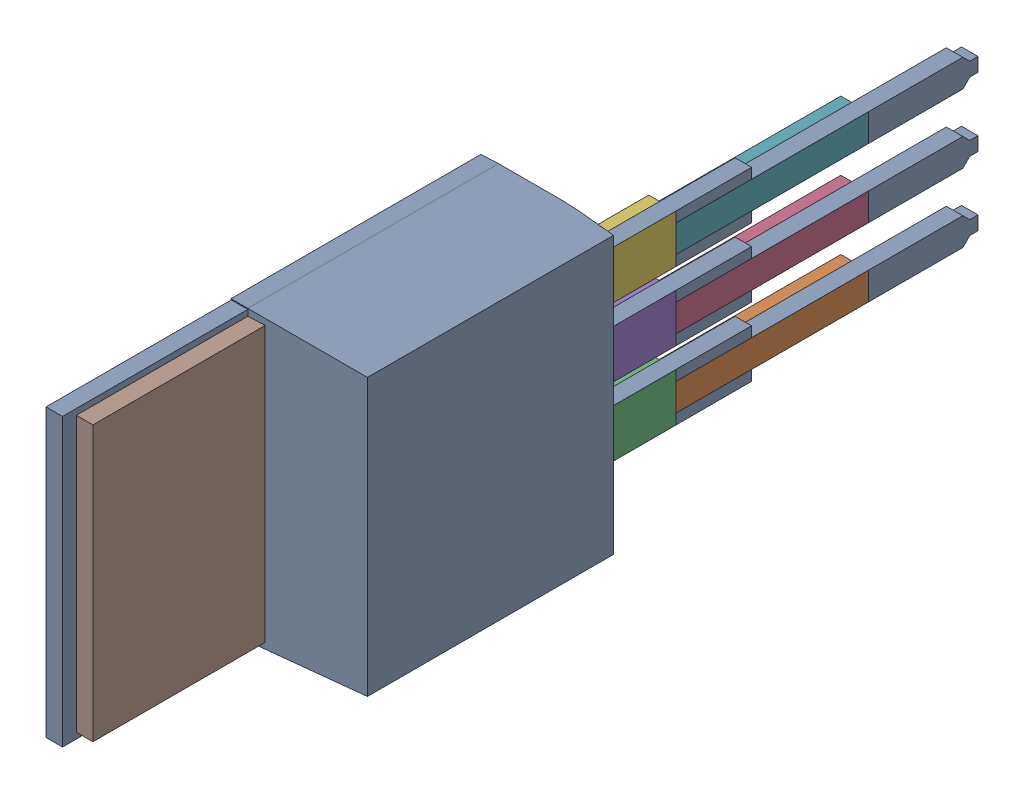
SolidWorks assembly Q2, configuration Default. Lengths in mm.
Overall size (4.86 10.67 30.99).
15 component instances, 4 part files, 0 mates.
Components (placement in the parent):
- 42ctq030-1: 42ctq030 [Default] at (98.0452 35.6871 7.62) x (0 1 0) z (1 0 0) size (10.67 30.99 4.83)
- 809727544-1: 809727544 [Default] at (97.5373 33.147 -3.048) size (1.02 1.02 7.11)
  - Extruded-1: Extruded [Default] at origin size (1.02 1.02 7.11)
- 809727680-1: 809727680 [Default] at (97.5373 33.147 4.064) size (1.02 1.78 4.06)
  - Extruded_2-1: Extruded_2 [Default] at origin size (1.02 1.78 4.06)
- 809727544-2: 809727544 [Default] at (97.5373 35.687 -3.048) size (1.02 1.02 7.11)
  - Extruded-1: Extruded [Default] at origin size (1.02 1.02 7.11)
- 809727680-2: 809727680 [Default] at (97.5373 35.687 4.064) size (1.02 1.78 4.06)
  - Extruded_2-1: Extruded_2 [Default] at origin size (1.02 1.78 4.06)
- 809727680-3: 809727680 [Default] at (97.5373 38.227 4.064) size (1.02 1.78 4.06)
  - Extruded_2-1: Extruded_2 [Default] at origin size (1.02 1.78 4.06)
- 809727544-3: 809727544 [Default] at (97.5373 38.227 -3.048) size (1.02 1.02 7.11)
  - Extruded-1: Extruded [Default] at origin size (1.02 1.02 7.11)
- 809727816-1: 809727816 [Default] at (95.1243 35.687 8.128) size (1.27 10.16 15.24)
  - Extruded_3-1: Extruded_3 [Default] at origin size (1.27 10.16 15.24)
